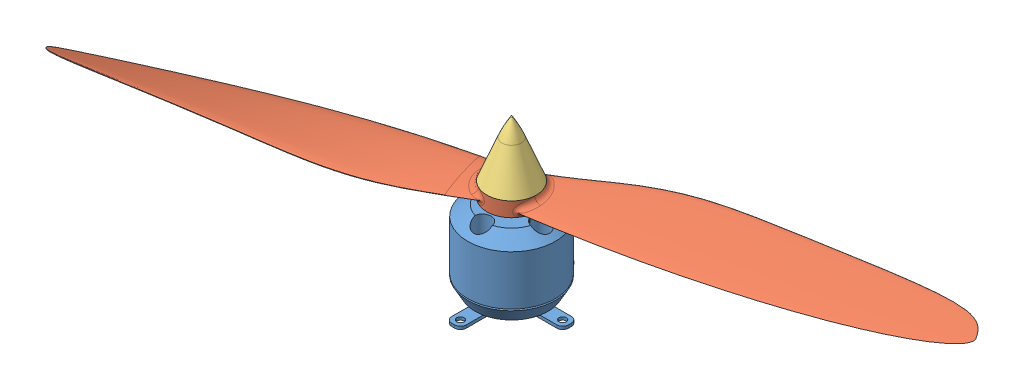
SolidWorks assembly Propulsion system assembly, configuration Default. Lengths in mm.
Overall size (257.04 52.9 102.49).
3 component instances, 3 part files, 4 mates.
Components (placement in the parent):
- Electric motor-1: Electric motor [Default] at (12.8913 -4.1913 35.7137) size (40 40.5 40)
- Propeller - 30deg twist-1: Propeller - 30deg twist [Default] at (9.5179 26.7661 36.8819) x (0.267188 0.098233 0.958624) z (-0.963211 -0.002607 0.268734) size (34.11 7.29 257.18)
- Propeller spinner-1: Propeller spinner [Default] at (12.8913 24.3087 35.7137) size (17 24.4 17)
Mates (geometry in assembly coordinates):
- Concentric1: concentric anti-aligned: cylinder of Electric motor-1 through (12.8913 -4.1913 35.7137) axis (0 -1 0) radius 1.585; circle of Propeller - 30deg twist-1
- Coincident1: coincident aligned: plane of Electric motor-1 through (17.8913 24.3087 35.7137) normal (0 1 0); circle of Propeller - 30deg twist-1
- Concentric2: concentric aligned: cylinder of Electric motor-1 through (12.8913 -4.1913 35.7137) axis (0 -1 0) radius 1.585; cylinder of Propeller spinner-1 through (12.8913 29.3087 35.7137) axis (0 -1 0) radius 1.585
- Coincident3: coincident aligned: circle of Electric motor-1; circle of Propeller spinner-1
